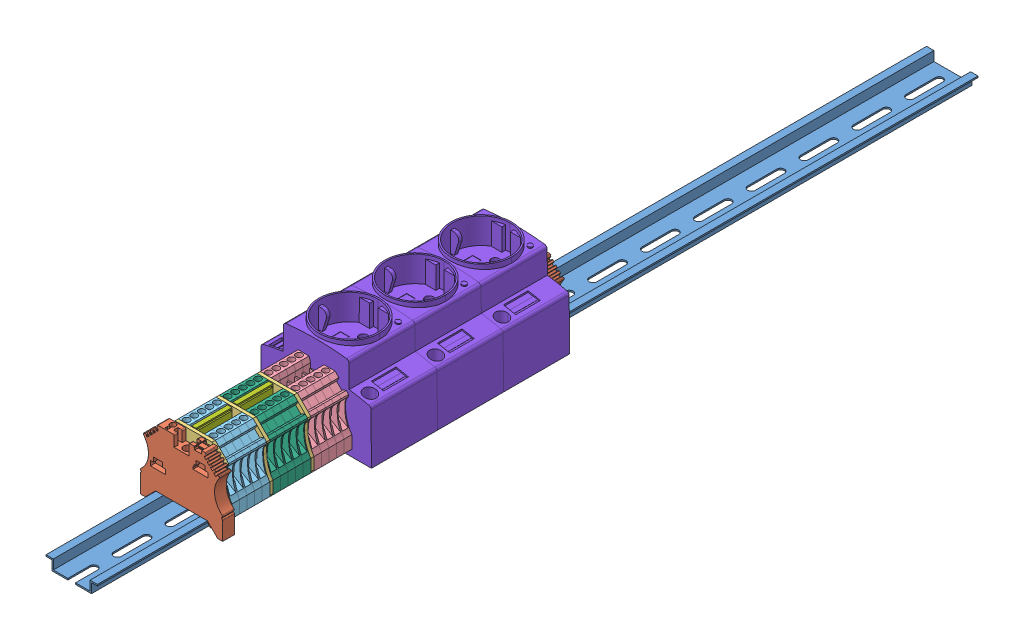
SolidWorks assembly 5xLNPE_Schuko-Raspi, configuration Standard. Lengths in mm.
Overall size (75.48 67.56 600).
26 component instances, 8 part files, 78 mates.
Components (placement in the parent):
- Hutschiene-1: Hutschiene [600] at (-17.5 -7.5 -600) size (35 7.5 600)
- WEW_35_2-1: WEW_35_2 [Standard] at (-45.75 -7 -309.85) x (0 0 1) z (0 1 0) size (8 56.1 46.5)
- WEW_35_2-2: WEW_35_2 [Standard] at (10.35 -7 -75) x (0 0 -1) z (0 1 0) size (8 56.1 46.5)
- D_UT_2.5_10-1: D_UT_2.5_10 [Standard] at (-46.4297 58.45 -85.2) size (47 39.8 2.2)
- D_UT_2.5_10-2: D_UT_2.5_10 [Standard] at (-46.4297 58.45 -113.15) size (47 39.8 2.2)
- D_UT_2.5_10-3: D_UT_2.5_10 [Standard] at (-46.4297 58.45 -141.1) size (47 39.8 2.2)
- UT_2.5_PE-1: UT_2.5_PE [Standard] at (-48.6989 10.6178 -141.1) x (0.992546 -0.121869 0) z (0 0 1) size (49.27 50.96 5.15)
- UT_2.5_PE-2: UT_2.5_PE [Standard] at (-48.6989 10.6178 -146.25) x (0.992546 -0.121869 0) z (0 0 1) size (49.27 50.96 5.15)
- UT_2.5_PE-3: UT_2.5_PE [Standard] at (-48.6989 10.6178 -151.4) x (0.992546 -0.121869 0) z (0 0 1) size (49.27 50.96 5.15)
- UT_2.5_PE-4: UT_2.5_PE [Standard] at (-48.6989 10.6178 -156.55) x (0.992546 -0.121869 0) z (0 0 1) size (49.27 50.96 5.15)
- UT_2.5_PE-5: UT_2.5_PE [Standard] at (-48.6989 10.6178 -161.7) x (0.992546 -0.121869 0) z (0 0 1) size (49.27 50.96 5.15)
- UT_2.5-1: UT_2.5 [Standard] at (-48.6989 10.6178 -85.2) x (0.992546 -0.121869 0) z (0 0 1) size (49.27 50.96 5.15)
- UT_2.5-2: UT_2.5 [Standard] at (-48.6989 10.6178 -90.35) x (0.992546 -0.121869 0) z (0 0 1) size (49.27 50.96 5.15)
- UT_2.5-3: UT_2.5 [Standard] at (-48.6989 10.6178 -95.5) x (0.992546 -0.121869 0) z (0 0 1) size (49.27 50.96 5.15)
- UT_2.5-4: UT_2.5 [Standard] at (-48.6989 10.6178 -100.65) x (0.992546 -0.121869 0) z (0 0 1) size (49.27 50.96 5.15)
- UT_2.5-5: UT_2.5 [Standard] at (-48.6989 10.6178 -105.8) x (0.992546 -0.121869 0) z (0 0 1) size (49.27 50.96 5.15)
- UT_2.5_BU-1: UT_2.5_BU [Standard] at (-48.6989 10.6178 -113.15) x (0.992546 -0.121869 0) z (0 0 1) size (49.27 50.96 5.15)
- UT_2.5_BU-2: UT_2.5_BU [Standard] at (-48.6989 10.6178 -118.3) x (0.992546 -0.121869 0) z (0 0 1) size (49.27 50.96 5.15)
- UT_2.5_BU-3: UT_2.5_BU [Standard] at (-48.6989 10.6178 -123.45) x (0.992546 -0.121869 0) z (0 0 1) size (49.27 50.96 5.15)
- UT_2.5_BU-4: UT_2.5_BU [Standard] at (-48.6989 10.6178 -128.6) x (0.992546 -0.121869 0) z (0 0 1) size (49.27 50.96 5.15)
- UT_2.5_BU-5: UT_2.5_BU [Standard] at (-48.6989 10.6178 -133.75) x (0.992546 -0.121869 0) z (0 0 1) size (49.27 50.96 5.15)
- FBS_5_5-1: FBS_5_5 [Standard] at (-24.1072 48.875 -144.035) size (3 22.98 24.6)
- FBS_5_5-2: FBS_5_5 [Standard] at (-24.1072 48.875 -171.985) size (3 22.98 24.6)
- EO_CF_UT_LED-1: EO_CF_UT_LED [Standard] at (-87.0914 -21.0563 -191.6) size (75.48 61.64 45)
- EO_CF_UT_LED-2: EO_CF_UT_LED [Standard] at (-87.0914 -21.0563 -236.6) size (75.48 61.64 45)
- EO_CF_UT_LED-3: EO_CF_UT_LED [Standard] at (-87.0914 -21.0563 -281.6) size (75.48 61.64 45)
Mates (geometry in assembly coordinates):
- Deckungsgleich1: coincident aligned: plane of Hutschiene-1 through (-17.5 -7.5 0) normal (0 0 1); plane of assembly through (0 0 0) normal (0 0 1)
- Deckungsgleich2: coincident aligned: plane of Hutschiene-1 through (-30 0 0) normal (0 1 0); plane of assembly through (0 0 0) normal (0 1 0)
- Deckungsgleich3: coincident aligned: plane of Hutschiene-1 through (0 -1 0) normal (1 0 0); plane of assembly through (0 0 0) normal (1 0 0)
- Abstand1: distance = 75 mm aligned: plane of WEW_35_2-2 through (-17.7 0 -75) normal (0 0 1); plane of Hutschiene-1 through (-17.5 -7.5 0) normal (0 0 1)
- Deckungsgleich70: coincident anti-aligned: plane of Hutschiene-1 through (0 0 0) normal (0 1 0); plane of EO_CF_UT_LED-1 through (-54.05 0 -193.75) normal (0 -1 0)
- Deckungsgleich71: coincident anti-aligned: plane of Hutschiene-1 through (-30 0 0) normal (0 1 0); plane of EO_CF_UT_LED-2 through (-54.05 0 -238.75) normal (0 -1 0)
- Deckungsgleich72: coincident anti-aligned: plane of Hutschiene-1 through (-30 0 0) normal (0 1 0); plane of EO_CF_UT_LED-3 through (-54.05 0 -283.75) normal (0 -1 0)
- Deckungsgleich73: coincident anti-aligned: plane of Hutschiene-1 through (0 -1 0) normal (1 0 0); plane of EO_CF_UT_LED-1 through (0 8.9 -167.85) normal (-1 0 0)
- Deckungsgleich74: coincident anti-aligned: plane of Hutschiene-1 through (0 -1 0) normal (1 0 0); plane of EO_CF_UT_LED-2 through (0 8.9 -212.85) normal (-1 0 0)
- Deckungsgleich75: coincident anti-aligned: plane of Hutschiene-1 through (0 -1 0) normal (1 0 0); plane of EO_CF_UT_LED-3 through (0 8.9 -257.85) normal (-1 0 0)
- Deckungsgleich77: coincident anti-aligned: plane of EO_CF_UT_LED-1 through (-17.75 2.45 -211.85) normal (0 0 -1); plane of EO_CF_UT_LED-2 through (-17.75 2.45 -211.85) normal (0 0 1)
- Deckungsgleich78: coincident anti-aligned: plane of EO_CF_UT_LED-2 through (-17.75 2.45 -256.85) normal (0 0 -1); plane of EO_CF_UT_LED-3 through (-17.75 2.45 -256.85) normal (0 0 1)
- Deckungsgleich81: coincident anti-aligned: plane of Hutschiene-1 through (-30 0 0) normal (0 1 0); plane of WEW_35_2-2 through (-35.4 0 -83) normal (0 -1 0)
- Deckungsgleich82: coincident anti-aligned: plane of Hutschiene-1 through (-30 0 0) normal (0 1 0); plane of UT_2.5-1 through (-7.7 0 -85.2) normal (0 -1 0)
- Deckungsgleich83: coincident anti-aligned: plane of Hutschiene-1 through (-30 0 0) normal (0 1 0); plane of UT_2.5-2 through (-7.7 0 -90.35) normal (0 -1 0)
- Deckungsgleich84: coincident anti-aligned: plane of Hutschiene-1 through (-30 0 0) normal (0 1 0); plane of UT_2.5-3 through (-7.7 0 -95.5) normal (0 -1 0)
- Deckungsgleich85: coincident anti-aligned: plane of Hutschiene-1 through (-30 0 0) normal (0 1 0); plane of UT_2.5-4 through (-7.7 0 -100.65) normal (0 -1 0)
- Deckungsgleich86: coincident anti-aligned: plane of Hutschiene-1 through (-30 0 0) normal (0 1 0); plane of UT_2.5-5 through (-7.7 0 -105.8) normal (0 -1 0)
- Deckungsgleich87: coincident aligned: plane of D_UT_2.5_10-1 through (4.3 30.8 -84.1) normal (1 0 0); plane of UT_2.5-1 through (4.3 30.8 -85.2) normal (1 0 0)
- Deckungsgleich88: coincident aligned: line of D_UT_2.5_10-1 through (4.3 29.6 -85.2) axis (0 0 1); line of UT_2.5-1 through (4.3 29.6 -90.35) axis (0 0 1)
- Deckungsgleich89: coincident anti-aligned: plane of D_UT_2.5_10-1 through (8.926 -3.78 -85.2) normal (0 0 -1); plane of UT_2.5-1 through (0 0 -85.2) normal (0 0 1)
- Deckungsgleich90: coincident anti-aligned: plane of UT_2.5-1 through (0 0 -90.35) normal (0 0 -1); plane of UT_2.5-2 through (0 0 -90.35) normal (0 0 1)
- Deckungsgleich91: coincident anti-aligned: plane of UT_2.5-2 through (0 0 -95.5) normal (0 0 -1); plane of UT_2.5-3 through (0 0 -95.5) normal (0 0 1)
- Deckungsgleich92: coincident anti-aligned: plane of UT_2.5-3 through (0 0 -100.65) normal (0 0 -1); plane of UT_2.5-4 through (0 0 -100.65) normal (0 0 1)
- Deckungsgleich93: coincident anti-aligned: plane of UT_2.5-4 through (0 0 -105.8) normal (0 0 -1); plane of UT_2.5-5 through (0 0 -105.8) normal (0 0 1)
- Deckungsgleich94: coincident anti-aligned: plane of Hutschiene-1 through (0 -1 0) normal (1 0 0); plane of UT_2.5-1 through (0 -1.1 -85.2) normal (-1 0 0)
- Deckungsgleich95: coincident anti-aligned: plane of Hutschiene-1 through (0 -1 0) normal (1 0 0); plane of UT_2.5-2 through (0 -1.1 -90.35) normal (-1 0 0)
- Deckungsgleich96: coincident anti-aligned: plane of Hutschiene-1 through (0 -1 0) normal (1 0 0); plane of UT_2.5-3 through (0 -1.1 -95.5) normal (-1 0 0)
- Deckungsgleich97: coincident anti-aligned: plane of Hutschiene-1 through (0 -1 0) normal (1 0 0); plane of UT_2.5-4 through (0 -1.1 -100.65) normal (-1 0 0)
- Deckungsgleich98: coincident anti-aligned: plane of Hutschiene-1 through (0 -1 0) normal (1 0 0); plane of UT_2.5-5 through (0 -1.1 -105.8) normal (-1 0 0)
- Deckungsgleich99: coincident anti-aligned: plane of WEW_35_2-2 through (-17.7 0 -83) normal (0 0 -1); plane of D_UT_2.5_10-1 through (-31.3534 31.331 -83) normal (0 0 1)
- Deckungsgleich101: coincident: plane of Hutschiene-1 through (0 -1 0) normal (1 0 0); line of WEW_35_2-2 through (0 0 -83) axis (0 0 1)
- Deckungsgleich102: coincident anti-aligned: plane of UT_2.5-1 through (-18.35 21.85 -85.675) normal (0 0 -1); plane of FBS_5_5-1 through (-18.5 39.7 -85.675) normal (0 0 1)
- Deckungsgleich103: coincident anti-aligned: plane of UT_2.5-2 through (-21.5 36.703 -90.35) normal (1 0 0); plane of FBS_5_5-1 through (-21.5 38.7586 -99.6095) normal (-1 0 0)
- Deckungsgleich104: coincident aligned: plane of UT_2.5-1 through (-30.1 40 -85.2) normal (0 1 0); plane of FBS_5_5-1 through (-18.5 40 -96.075) normal (0 1 0)
- Deckungsgleich105: coincident anti-aligned: plane of D_UT_2.5_10-2 through (8.926 -3.78 -113.15) normal (0 0 -1); plane of UT_2.5_BU-1 through (0 0 -113.15) normal (0 0 1)
- Deckungsgleich106: coincident anti-aligned: plane of UT_2.5_BU-1 through (0 0 -118.3) normal (0 0 -1); plane of UT_2.5_BU-2 through (0 0 -118.3) normal (0 0 1)
- Deckungsgleich107: coincident anti-aligned: plane of UT_2.5_BU-2 through (0 0 -123.45) normal (0 0 -1); plane of UT_2.5_BU-3 through (0 0 -123.45) normal (0 0 1)
- Deckungsgleich108: coincident anti-aligned: plane of UT_2.5_BU-3 through (0 0 -128.6) normal (0 0 -1); plane of UT_2.5_BU-4 through (0 0 -128.6) normal (0 0 1)
- Deckungsgleich109: coincident anti-aligned: plane of UT_2.5_BU-4 through (0 0 -133.75) normal (0 0 -1); plane of UT_2.5_BU-5 through (0 0 -133.75) normal (0 0 1)
- Deckungsgleich110: coincident anti-aligned: plane of Hutschiene-1 through (-30 0 0) normal (0 1 0); plane of UT_2.5_BU-1 through (-7.7 0 -113.15) normal (0 -1 0)
- Deckungsgleich111: coincident anti-aligned: plane of Hutschiene-1 through (-30 0 0) normal (0 1 0); plane of UT_2.5_BU-2 through (-7.7 0 -118.3) normal (0 -1 0)
- Deckungsgleich112: coincident anti-aligned: plane of Hutschiene-1 through (-30 0 0) normal (0 1 0); plane of UT_2.5_BU-3 through (-7.7 0 -123.45) normal (0 -1 0)
- Deckungsgleich113: coincident anti-aligned: plane of Hutschiene-1 through (-30 0 0) normal (0 1 0); plane of UT_2.5_BU-4 through (-7.7 0 -128.6) normal (0 -1 0)
- Deckungsgleich114: coincident anti-aligned: plane of Hutschiene-1 through (-30 0 0) normal (0 1 0); plane of UT_2.5_BU-5 through (-7.7 0 -133.75) normal (0 -1 0)
- Deckungsgleich115: coincident aligned: plane of D_UT_2.5_10-2 through (4.3 30.8 -112.05) normal (1 0 0); plane of UT_2.5_BU-1 through (4.3 30.8 -113.15) normal (1 0 0)
- Deckungsgleich116: coincident aligned: line of D_UT_2.5_10-2 through (4.3 29.6 -113.15) axis (0 0 1); line of UT_2.5_BU-1 through (4.3 29.6 -118.3) axis (0 0 1)
- Deckungsgleich117: coincident anti-aligned: plane of Hutschiene-1 through (0 -1 0) normal (1 0 0); plane of UT_2.5_BU-1 through (0 -1.1 -113.15) normal (-1 0 0)
- Deckungsgleich118: coincident anti-aligned: plane of Hutschiene-1 through (0 -1 0) normal (1 0 0); plane of UT_2.5_BU-2 through (0 -1.1 -118.3) normal (-1 0 0)
- Deckungsgleich119: coincident anti-aligned: plane of Hutschiene-1 through (0 -1 0) normal (1 0 0); plane of UT_2.5_BU-3 through (0 -1.1 -123.45) normal (-1 0 0)
- Deckungsgleich120: coincident anti-aligned: plane of Hutschiene-1 through (0 -1 0) normal (1 0 0); plane of UT_2.5_BU-4 through (0 -1.1 -128.6) normal (-1 0 0)
- Deckungsgleich121: coincident anti-aligned: plane of Hutschiene-1 through (0 -1 0) normal (1 0 0); plane of UT_2.5_BU-5 through (0 -1.1 -133.75) normal (-1 0 0)
- Deckungsgleich122: coincident anti-aligned: plane of D_UT_2.5_10-2 through (-31.3534 31.331 -110.95) normal (0 0 1); plane of UT_2.5-5 through (0 0 -110.95) normal (0 0 -1)
- Deckungsgleich123: coincident anti-aligned: plane of UT_2.5_BU-1 through (-18.35 21.85 -113.625) normal (0 0 -1); plane of FBS_5_5-2 through (-18.5 39.7 -113.625) normal (0 0 1)
- Deckungsgleich124: coincident anti-aligned: plane of UT_2.5_BU-1 through (-21.5 36.703 -113.15) normal (1 0 0); plane of FBS_5_5-2 through (-21.5 38.7586 -127.5595) normal (-1 0 0)
- Deckungsgleich125: coincident aligned: plane of UT_2.5_BU-1 through (-30.1 40 -113.15) normal (0 1 0); plane of FBS_5_5-2 through (-18.5 40 -124.025) normal (0 1 0)
- Deckungsgleich126: coincident anti-aligned: plane of D_UT_2.5_10-3 through (8.926 -3.78 -141.1) normal (0 0 -1); plane of UT_2.5_PE-1 through (0 0 -141.1) normal (0 0 1)
- Deckungsgleich127: coincident anti-aligned: plane of UT_2.5_PE-1 through (0 0 -146.25) normal (0 0 -1); plane of UT_2.5_PE-2 through (0 0 -146.25) normal (0 0 1)
- Deckungsgleich128: coincident anti-aligned: plane of UT_2.5_PE-2 through (0 0 -151.4) normal (0 0 -1); plane of UT_2.5_PE-3 through (0 0 -151.4) normal (0 0 1)
- Deckungsgleich129: coincident anti-aligned: plane of UT_2.5_PE-3 through (0 0 -156.55) normal (0 0 -1); plane of UT_2.5_PE-4 through (0 0 -156.55) normal (0 0 1)
- Deckungsgleich130: coincident anti-aligned: plane of UT_2.5_PE-4 through (0 0 -161.7) normal (0 0 -1); plane of UT_2.5_PE-5 through (0 0 -161.7) normal (0 0 1)
- Deckungsgleich131: coincident aligned: plane of D_UT_2.5_10-3 through (4.3 30.8 -140) normal (1 0 0); plane of UT_2.5_PE-1 through (4.3 30.8 -141.1) normal (1 0 0)
- Deckungsgleich132: coincident aligned: line of D_UT_2.5_10-3 through (4.3 30.8 -141.1) axis (0 0 1); line of UT_2.5_PE-1 through (4.3 30.8 -146.25) axis (0 0 1)
- Deckungsgleich133: coincident anti-aligned: plane of Hutschiene-1 through (-30 0 0) normal (0 1 0); plane of UT_2.5_PE-5 through (-7.7 0 -161.7) normal (0 -1 0)
- Deckungsgleich134: coincident anti-aligned: plane of Hutschiene-1 through (-30 0 0) normal (0 1 0); plane of UT_2.5_PE-4 through (-7.7 0 -156.55) normal (0 -1 0)
- Deckungsgleich135: coincident anti-aligned: plane of Hutschiene-1 through (-30 0 0) normal (0 1 0); plane of UT_2.5_PE-3 through (-7.7 0 -151.4) normal (0 -1 0)
- Deckungsgleich136: coincident anti-aligned: plane of Hutschiene-1 through (-30 0 0) normal (0 1 0); plane of UT_2.5_PE-2 through (-7.7 0 -146.25) normal (0 -1 0)
- Deckungsgleich137: coincident anti-aligned: plane of Hutschiene-1 through (-30 0 0) normal (0 1 0); plane of UT_2.5_PE-1 through (-7.7 0 -141.1) normal (0 -1 0)
- Deckungsgleich138: coincident anti-aligned: plane of Hutschiene-1 through (0 -1 0) normal (1 0 0); plane of UT_2.5_PE-1 through (0 -1.1 -141.1) normal (-1 0 0)
- Deckungsgleich139: coincident anti-aligned: plane of Hutschiene-1 through (0 -1 0) normal (1 0 0); plane of UT_2.5_PE-2 through (0 -1.1 -146.25) normal (-1 0 0)
- Deckungsgleich140: coincident anti-aligned: plane of Hutschiene-1 through (0 -1 0) normal (1 0 0); plane of UT_2.5_PE-3 through (0 -1.1 -151.4) normal (-1 0 0)
- Deckungsgleich141: coincident anti-aligned: plane of Hutschiene-1 through (0 -1 0) normal (1 0 0); plane of UT_2.5_PE-4 through (0 -1.1 -156.55) normal (-1 0 0)
- Deckungsgleich142: coincident anti-aligned: plane of Hutschiene-1 through (0 -1 0) normal (1 0 0); plane of UT_2.5_PE-5 through (0 -1.1 -161.7) normal (-1 0 0)
- Deckungsgleich143: coincident anti-aligned: plane of D_UT_2.5_10-3 through (-31.3534 31.331 -138.9) normal (0 0 1); plane of UT_2.5_BU-5 through (0 0 -138.9) normal (0 0 -1)
- Deckungsgleich144: coincident anti-aligned: plane of UT_2.5_PE-5 through (0 0 -166.85) normal (0 0 -1); plane of EO_CF_UT_LED-1 through (-17.75 2.45 -166.85) normal (0 0 1)
- Deckungsgleich145: coincident: plane of WEW_35_2-1 through (-17.7 0 -301.85) normal (0 0 1); plane of EO_CF_UT_LED-3 through (-17.75 2.45 -301.85) normal (0 0 -1)
- Deckungsgleich146: coincident: plane of Hutschiene-1 through (0 0 0) normal (0 1 0); plane of WEW_35_2-1 through (0 0 -301.85) normal (0 -1 0)
- Deckungsgleich147: coincident anti-aligned: line of Hutschiene-1 through (0 0 0) axis (0 0 -1); line of WEW_35_2-1 through (0 0 -309.85) axis (0 0 1)
